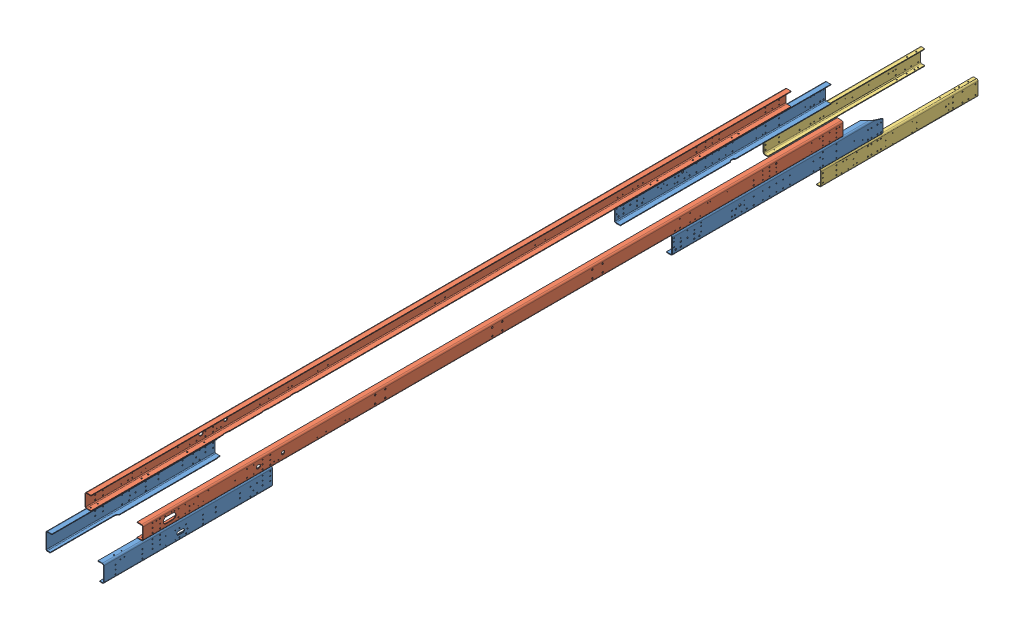
SolidWorks assembly 3602-CC1-158, configuration Default. Lengths in mm.
Overall size (869.95 698.5 13128.63).
12 component instances, 3 part files, 12 mates.
Components (placement in the parent):
- 4129-CC1-1: 4129-CC1 [Both Rails] at origin size (869.95 260.35 2530.47)
  - 1982-CC1-1: 1982-CC1 [1982-CC1-100] at (434.975 0 1844.675) size (88.9 260.35 2530.47)
  - 1982-CC1-2: 1982-CC1 [1982-CC1-100] at (-434.975 0 -685.8) x (-1 0 0) z (0 0 -1) size (88.9 260.35 2530.47)
- 4128-CC1-1: 4128-CC1 [Both Rails] at (0 260.35 0) size (869.95 209.55 10515.6)
  - 1500-CC1-3: 1500-CC1 [1500-CC1-414] at (434.975 0 1257.3) size (88.9 209.55 10515.6)
  - 1500-CC1-5: 1500-CC1 [1500-CC1-414] at (-434.975 0 -9258.3) x (-1 0 0) z (0 0 -1) size (88.9 209.55 10515.6)
- 3994-CC1-1: 3994-CC1 [Both Rails] at (0 0 -8026.4) size (869.95 260.35 3162.3)
  - 1982-CC1-1: 1982-CC1 [1982-CC1-124.50] at (434.975 0 1333.5) size (88.9 260.35 3162.3)
  - 1982-CC1-2: 1982-CC1 [1982-CC1-124.50] at (-434.975 0 -1828.8) x (-1 0 0) z (0 0 -1) size (88.9 260.35 3162.3)
- 4307-CC1-1: 4307-CC1 [Both Rails] at (0 -228.6 -9829.8) size (869.95 228.6 2355.85)
  - 3623-CC1-5: 3623-CC1 [3623-CC1-92.75] at (434.975 0 901.7) size (69.85 228.6 2355.85)
  - 3623-CC1-4: 3623-CC1 [3623-CC1-92.75] at (-434.975 0 -1454.15) x (-1 0 0) z (0 0 -1) size (69.85 228.6 2355.85)
Mates (geometry in assembly coordinates):
- Coincident8: coincident aligned: plane of ?; plane of assembly
- Coincident9: coincident aligned: plane of ?; plane of assembly
- Coincident10: coincident aligned: plane of ?; plane of assembly
- Coincident11: coincident aligned: plane of ?; plane of assembly
- Coincident12: coincident aligned: plane of assembly; plane of ?
- Coincident13: coincident aligned: plane of ?; plane of assembly
- Coincident20: coincident aligned: plane of ?; plane of assembly
- Coincident21: coincident aligned: plane of ?; plane of assembly
- Distance2: distance = 1803.4 mm aligned: plane of ?; plane of assembly
- Coincident22: coincident aligned: plane of ?; plane of assembly
- Coincident23: coincident aligned: plane of ?; plane of ?
- Coincident24: coincident aligned: plane of ?; plane of assembly
